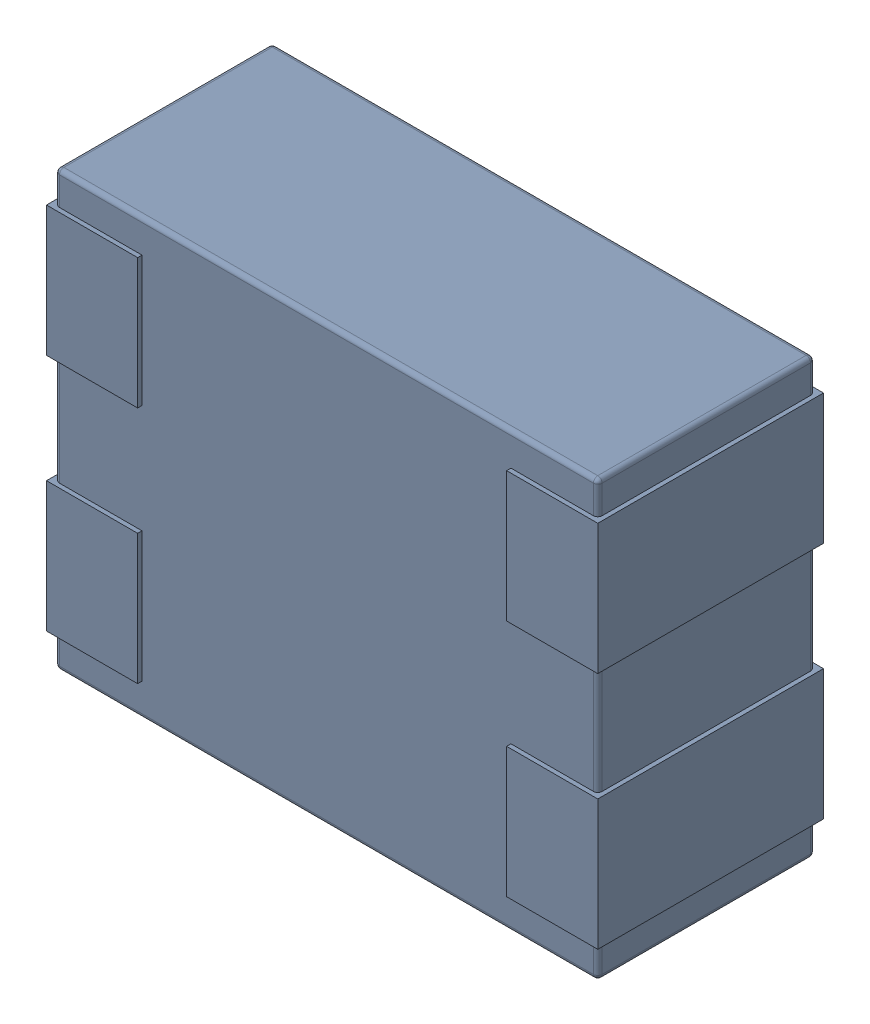
SolidWorks assembly L15, configuration Défaut. Lengths in mm.
Overall size (1.27 1 0.52).
4 component instances, 1 part files, 0 mates.
Components (placement in the parent):
- MCZ1210DH900L2TA0G-1: MCZ1210DH900L2TA0G [Défaut] at (76.7165 -29.5751 -1.6) x (0 -1 0) z (0 0 1) size (1 1.27 0.52)
  - 3D_PCB1_2021-12-30 (1).step-1: 3D_PCB1_2021-12-30 (1).step [Défaut] at origin size (1 1.27 0.52)
    - a3ec64f90eb5404ebd79eca0046a794a.step-1: a3ec64f90eb5404ebd79eca0046a794a.step [Défaut] at (5.0419 -6.8961 1.6) size (1 1.27 0.52)
      - SOLID.step_650-1: SOLID.step_650 [Défaut] at origin size (1 1.27 0.52)
